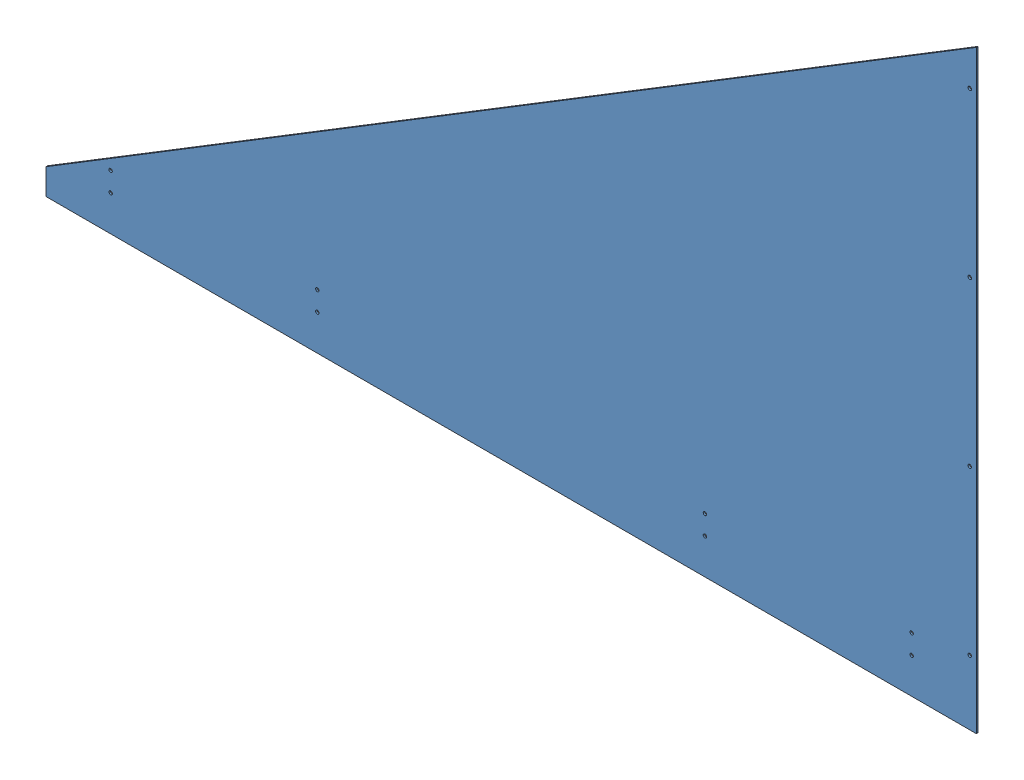
SolidWorks assembly GE-20332, configuration GE-20332-Red. Lengths in mm.
Overall size (1828.8 1168.4 3.43).
2 component instances, 2 part files, 3 mates.
Components (placement in the parent):
- GE-20327-1: GE-20327 [Default] at origin size (1828.8 1168.4 3.17)
- GE-20332-Vinyl-1: GE-20332-Vinyl [GE-20332-Red-Vinyl] at (0 0 -0.254) size (1828.8 1168.4 0.25)
Mates (geometry in assembly coordinates):
- Coincident1: coincident anti-aligned: plane of GE-20327-1 through (0 0 0) normal (0 0 -1); plane of GE-20332-Vinyl-1 through (0 -50.8 0) normal (0 0 1)
- Coincident2: coincident aligned: plane of GE-20327-1 through (1828.8 1117.6 3.175) normal (1 0 0); plane of GE-20332-Vinyl-1 through (1828.8 1117.6 2.921) normal (1 0 0)
- Coincident3: coincident aligned: plane of GE-20327-1 through (1828.8 -50.8 1832.6804) normal (0 -1 0); plane of GE-20332-Vinyl-1 through (1828.8 -50.8 1832.4264) normal (0 -1 0)
